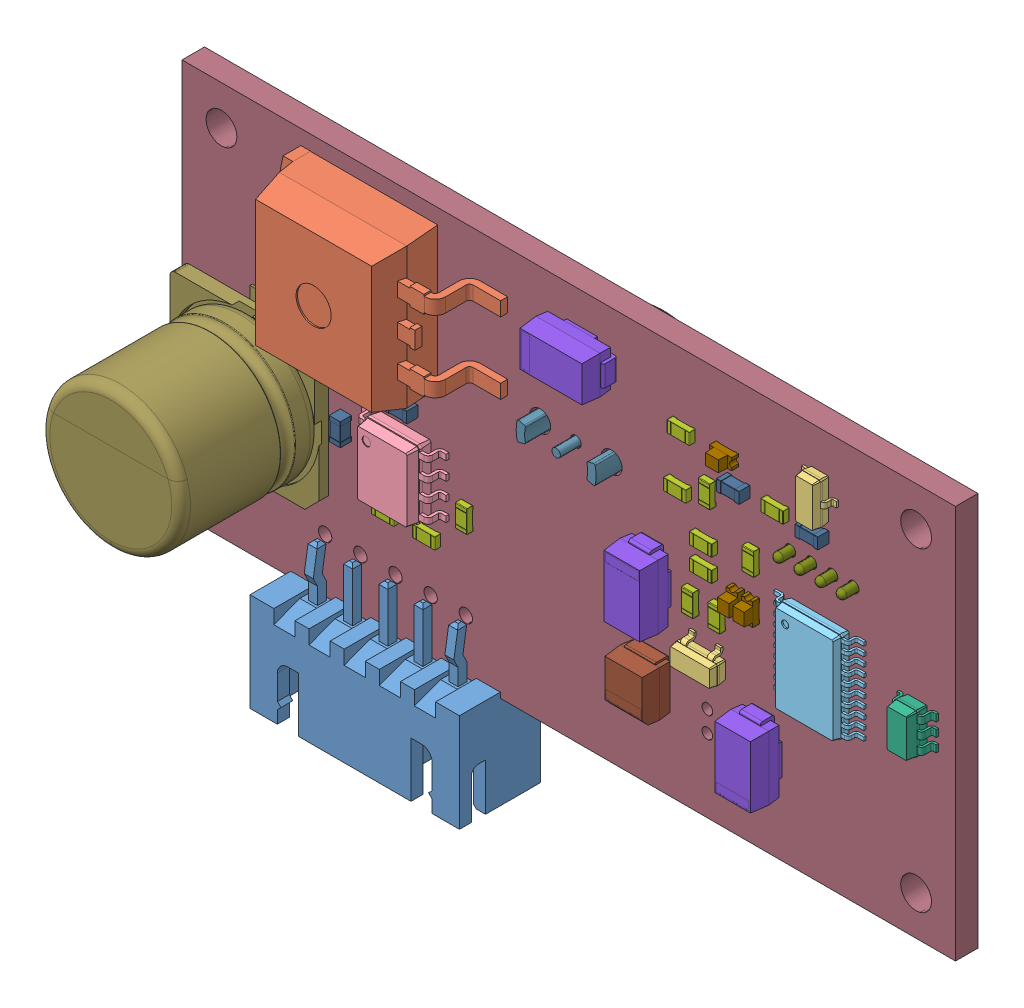
SolidWorks assembly pcb, configuration По умолчанию. Lengths in mm.
Overall size (56.35 34.62 18.7).
66 component instances, 16 part files, 9 mates.
Components (placement in the parent):
- JST_XH_B5B-XH-A_1x05_P2.50mm_Vertical.step-1: JST_XH_B5B-XH-A_1x05_P2.50mm_Vertical.step [По умолчанию] at (27.178 -43.124 2.15) x (1 0 0) z (0 -1 0) size (14.9 5.75 10.4)
  - SOLID.step-1: SOLID.step [По умолчанию] at origin size (14.9 5.75 10.4)
- TO-263-2.step-1: TO-263-2.step [По умолчанию] at (32.7 -21.5 1.65) x (-1 0 0) z (0 0 1) size (15 10 4.42)
  - SOLID-0.step-1: SOLID-0.step [По умолчанию] at origin size (15 10 4.42)
- SOT-23.step-1: SOT-23.step [По умолчанию] at (62.484 -19.431 1.65) size (2.5 3 1.2)
  - SOLID-1.step-1: SOLID-1.step [По умолчанию] at origin size (2.5 3 1.2)
- SOIC-8_3.9x4.9mm_P1.27mm.step-1: SOIC-8_3.9x4.9mm_P1.27mm.step [По умолчанию] at (33.02 -32.258 1.65) size (6 4.9 1.75)
  - SOLID-2.step-1: SOLID-2.step [По умолчанию] at origin size (6 4.9 1.75)
- TSSOP-20_4.4x6.5mm_P0.65mm.step-1: TSSOP-20_4.4x6.5mm_P0.65mm.step [По умолчанию] at (62.484 -29.972 1.65) size (6.4 6.5 1.2)
  - SOLID-3.step-1: SOLID-3.step [По умолчанию] at origin size (6.4 6.5 1.2)
- SOT-23-6.step-1: SOT-23-6.step [По умолчанию] at (69.426 -29.972 1.65) size (2.8 2.9 1.55)
  - SOLID-4.step-1: SOLID-4.step [По умолчанию] at origin size (2.8 2.9 1.55)
- R_0603_1608Metric.step-1: R_0603_1608Metric.step [По умолчанию] at (54.356 -26.416 1.65) x (-1 0 0) z (0 0 1) size (1.6 0.8 0.45)
  - SOLID-5.step-1: SOLID-5.step [По умолчанию] at origin size (1.6 0.8 0.45)
- R_0603_1608Metric.step-2: R_0603_1608Metric.step [По умолчанию] at (31.75 -35.814 1.65) x (-1 0 0) z (0 0 1) size (1.6 0.8 0.45)
  - SOLID-5.step-1: SOLID-5.step [По умолчанию] at origin size (1.6 0.8 0.45)
- R_0603_1608Metric.step-3: R_0603_1608Metric.step [По умолчанию] at (34.67 -35.814 1.65) x (-1 0 0) z (0 0 1) size (1.6 0.8 0.45)
  - SOLID-5.step-1: SOLID-5.step [По умолчанию] at origin size (1.6 0.8 0.45)
- R_0603_1608Metric.step-4: R_0603_1608Metric.step [По умолчанию] at (37.338 -33.337 1.65) x (0 1 0) z (0 0 1) size (1.6 0.8 0.45)
  - SOLID-5.step-1: SOLID-5.step [По умолчанию] at origin size (1.6 0.8 0.45)
- R_0603_1608Metric.step-5: R_0603_1608Metric.step [По умолчанию] at (55.306 -30.48 1.65) x (0 1 0) z (0 0 1) size (1.6 0.8 0.45)
  - SOLID-5.step-1: SOLID-5.step [По умолчанию] at origin size (1.6 0.8 0.45)
- R_0603_1608Metric.step-6: R_0603_1608Metric.step [По умолчанию] at (52.515 -24.003 1.65) size (1.6 0.8 0.45)
  - SOLID-5.step-1: SOLID-5.step [По умолчанию] at origin size (1.6 0.8 0.45)
- R_0603_1608Metric.step-7: R_0603_1608Metric.step [По умолчанию] at (53.406 -30.48 1.65) x (0 1 0) z (0 0 1) size (1.6 0.8 0.45)
  - SOLID-5.step-1: SOLID-5.step [По умолчанию] at origin size (1.6 0.8 0.45)
- R_0603_1608Metric.step-8: R_0603_1608Metric.step [По умолчанию] at (54.61 -23.178 1.65) x (0 -1 0) z (0 0 1) size (1.6 0.8 0.45)
  - SOLID-5.step-1: SOLID-5.step [По умолчанию] at origin size (1.6 0.8 0.45)
- R_0603_1608Metric.step-9: R_0603_1608Metric.step [По умолчанию] at (52.769 -20.32 1.65) size (1.6 0.8 0.45)
  - SOLID-5.step-1: SOLID-5.step [По умолчанию] at origin size (1.6 0.8 0.45)
- R_0603_1608Metric.step-10: R_0603_1608Metric.step [По умолчанию] at (57.7215 -25.781 1.65) x (0 -1 0) z (0 0 1) size (1.6 0.8 0.45)
  - SOLID-5.step-1: SOLID-5.step [По умолчанию] at origin size (1.6 0.8 0.45)
- R_0603_1608Metric.step-11: R_0603_1608Metric.step [По умолчанию] at (54.356 -28.03 1.65) size (1.6 0.8 0.45)
  - SOLID-5.step-1: SOLID-5.step [По умолчанию] at origin size (1.6 0.8 0.45)
- R_0603_1608Metric.step-12: R_0603_1608Metric.step [По умолчанию] at (59.436 -21.844 1.65) x (-1 0 0) z (0 0 1) size (1.6 0.8 0.45)
  - SOLID-5.step-1: SOLID-5.step [По умолчанию] at origin size (1.6 0.8 0.45)
- SOT-23.step-2: SOT-23.step [По умолчанию] at (54.356 -33.616 1.65) x (0 -1 0) z (0 0 1) size (2.5 3 1.2)
  - SOLID-1.step-1: SOLID-1.step [По умолчанию] at origin size (2.5 3 1.2)
- D_SMA.step-1: D_SMA.step [По умолчанию] at (50.546 -30.616 1.65) x (0 -1 0) z (0 0 1) size (5 2.7 2.22)
  - SOLID-6.step-1: SOLID-6.step [По умолчанию] at origin size (5 2.7 2.22)
- D_SMA.step-2: D_SMA.step [По умолчанию] at (58.42 -37.211 1.65) x (0 1 0) z (0 0 1) size (5 2.7 2.22)
  - SOLID-6.step-1: SOLID-6.step [По умолчанию] at origin size (5 2.7 2.22)
- D_SMA.step-3: D_SMA.step [По умолчанию] at (45.5 -19 1.65) size (5 2.7 2.22)
  - SOLID-6.step-1: SOLID-6.step [По умолчанию] at origin size (5 2.7 2.22)
- LED_0603_1608Metric_Castellated.step-1: LED_0603_1608Metric_Castellated.step [По умолчанию] at (55.8295 -20.32 1.65) size (1.6 0.8 1.1)
  - SOLID-7.step-1: SOLID-7.step [По умолчанию] at origin size (1.6 0.8 1.1)
- LED_0603_1608Metric_Castellated.step-2: LED_0603_1608Metric_Castellated.step [По умолчанию] at (56.642 -28.8425 1.65) x (0 -1 0) z (0 0 1) size (1.6 0.8 1.1)
  - SOLID-7.step-1: SOLID-7.step [По умолчанию] at origin size (1.6 0.8 1.1)
- LED_0603_1608Metric_Castellated.step-3: LED_0603_1608Metric_Castellated.step [По умолчанию] at (57.7215 -28.8425 1.65) x (0 -1 0) z (0 0 1) size (1.6 0.8 1.1)
  - SOLID-7.step-1: SOLID-7.step [По умолчанию] at origin size (1.6 0.8 1.1)
- C_0603_1608Metric.step-1: C_0603_1608Metric.step [По умолчанию] at (62.243 -21.844 1.65) size (1.6 0.8 0.8)
  - SOLID-8.step-1: SOLID-8.step [По умолчанию] at origin size (1.6 0.8 0.8)
- CP_EIA-3528-21_Kemet-B.step-1: CP_EIA-3528-21_Kemet-B.step [По умолчанию] at (50.546 -36.576 1.65) x (0 1 0) z (0 0 1) size (3.5 2.8 2.1)
  - SOLID-9.step-1: SOLID-9.step [По умолчанию] at origin size (3.5 2.8 2.1)
- C_0603_1608Metric.step-2: C_0603_1608Metric.step [По умолчанию] at (33.02 -28.702 1.65) size (1.6 0.8 0.8)
  - SOLID-8.step-1: SOLID-8.step [По умолчанию] at origin size (1.6 0.8 0.8)
- C_0603_1608Metric.step-3: C_0603_1608Metric.step [По умолчанию] at (28.702 -32.118 1.65) x (0 -1 0) z (0 0 1) size (1.6 0.8 0.8)
  - SOLID-8.step-1: SOLID-8.step [По умолчанию] at origin size (1.6 0.8 0.8)
- CP_Elec_10x10.5.step-1: CP_Elec_10x10.5.step [По умолчанию] at (22.479 -32.766 1.65) x (0 1 0) z (0 0 1) size (13.47 13.66 10.5)
  - SOLID-10.step-1: SOLID-10.step [По умолчанию] at origin size (13.47 13.66 10.5)
- C_0603_1608Metric.step-4: C_0603_1608Metric.step [По умолчанию] at (56.642 -21.844 1.65) x (-1 0 0) z (0 0 1) size (1.6 0.8 0.8)
  - SOLID-8.step-1: SOLID-8.step [По умолчанию] at origin size (1.6 0.8 0.8)
- COMPOUND.step-1: COMPOUND.step [По умолчанию] at origin size (55 28 1.6)
- Magnet_conn-1: Magnet_conn [По умолчанию] at (45 -25 -0.7) x (0 -1 0) z (1 0 0) size (10 9.55 10)
- ZH_02x01_1.5mm-1: ZH_02x01_1.5mm [По умолчанию] at (53.906 -37.548 0) x (0 1 0) z (-1 0 0) size (4.5 5.72 4.53)
- ZH_04x01_1.5mm-1: ZH_04x01_1.5mm [По умолчанию] at (62.504 -23.632 0) x (1 0 0) z (0 1 0) size (7.5 7.2 3.5)
Mates (geometry in assembly coordinates):
- Концентричный1: concentric anti-aligned: cylinder of COMPOUND.step-1 through (45 -25 -0.8) axis (0 0 1) radius 0.381; cylinder of Magnet_conn-1 through (45 -25 3) axis (0 0 -1) radius 0.3
- Параллельность2: parallel anti-aligned: plane of Magnet_conn-1 through (45 -25 -0.7) normal (0 -1 0)
- Совпадение2: coincident anti-aligned: plane of COMPOUND.step-1 through (44.5 -29.5 0) normal (0 0 -1); plane of Magnet_conn-1 through (45 -25 0) normal (0 0 1)
- Концентричный4: concentric aligned: cylinder of COMPOUND.step-1 through (54.356 -36.798 -0.8) axis (0 0 1) radius 0.381; cylinder of ZH_02x01_1.5mm-1 through (54.356 -36.798 -3.7) axis (0 0 1) radius 0.325
- Параллельность3: parallel aligned: plane of COMPOUND.step-1 through (17 -43.5 0) normal (0 -1 0); plane of ZH_02x01_1.5mm-1 through (53.906 -39.798 -4.5) normal (0 -1 0)
- Совпадение4: coincident anti-aligned: plane of COMPOUND.step-1 through (44.5 -29.5 0) normal (0 0 -1); plane of ZH_02x01_1.5mm-1 through (53.906 -37.548 0) normal (0 0 1)
- Концентричный5: concentric aligned: cylinder of COMPOUND.step-1 through (60.254 -24.082 -0.8) axis (0 0 1) radius 0.381; cylinder of ZH_04x01_1.5mm-1 through (60.254 -24.082 -3.7) axis (0 0 1) radius 0.325
- Параллельность4: parallel aligned: plane of COMPOUND.step-1 through (72 -43.5 0) normal (1 0 0); plane of ZH_04x01_1.5mm-1 through (66.254 -23.632 -4.5) normal (1 0 0)
- Совпадение6: coincident anti-aligned: plane of COMPOUND.step-1 through (44.5 -29.5 0) normal (0 0 -1); plane of ZH_04x01_1.5mm-1 through (62.504 -23.632 0) normal (0 0 1)
